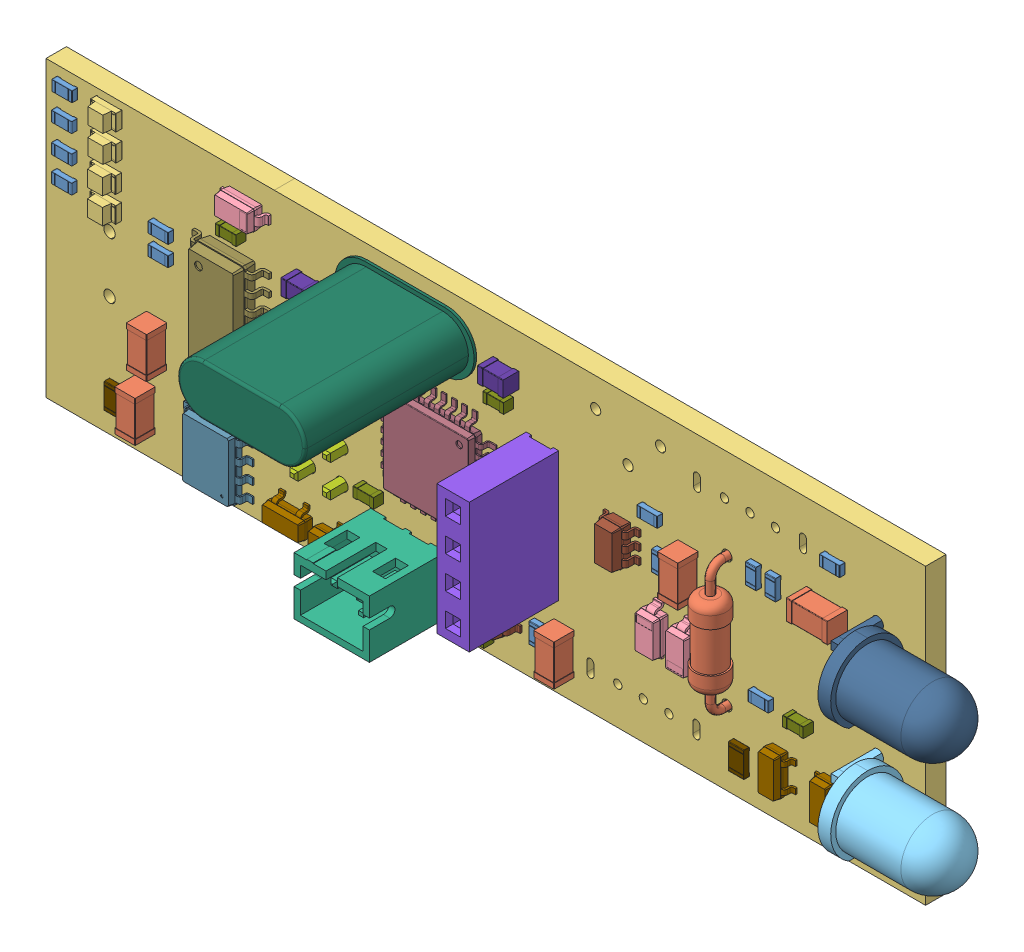
SolidWorks assembly RPM, configuration Default. Lengths in mm.
Overall size (76.12 23 23.34).
114 component instances, 21 part files, 0 mates.
Components (placement in the parent):
- RPM.step-1: RPM.step [Default] at origin size (76.12 23 23.34)
  - Mini_USB.step-1: Mini_USB.step [Default] at (183.35 -104.2 -0.05) x (1 0 0) z (0 0 -1) size (10.5 10.7 3.9)
    - SOLID.step-1: SOLID.step [Default] at origin size (10.5 10.7 3.9)
  - C_1206_3216Metric.step-1: C_1206_3216Metric.step [Default] at (220.5 -112.4 1.65) x (0 -1 0) z (0 0 1) size (3.2 1.6 1.6)
    - SOLID-0.step-1: SOLID-0.step [Default] at origin size (3.2 1.6 1.6)
  - C_1206_3216Metric.step-2: C_1206_3216Metric.step [Default] at (230.2 -102.2 1.65) x (0 1 0) z (0 0 1) size (3.2 1.6 1.6)
    - SOLID-0.step-1: SOLID-0.step [Default] at origin size (3.2 1.6 1.6)
  - C_1206_3216Metric.step-3: C_1206_3216Metric.step [Default] at (187.7 -112.275 1.65) x (0 1 0) z (0 0 1) size (3.2 1.6 1.6)
    - SOLID-0.step-1: SOLID-0.step [Default] at origin size (3.2 1.6 1.6)
  - C_1206_3216Metric.step-4: C_1206_3216Metric.step [Default] at (188.6 -107.5 1.65) x (0 1 0) z (0 0 1) size (3.2 1.6 1.6)
    - SOLID-0.step-1: SOLID-0.step [Default] at origin size (3.2 1.6 1.6)
  - LED_0805_2012Metric.step-1: LED_0805_2012Metric.step [Default] at (184.8625 -98.1 1.65) x (-1 0 0) z (0 0 1) size (2 1.25 1.1)
    - SOLID-1.step-1: SOLID-1.step [Default] at origin size (2 1.25 1.1)
  - LED_0805_2012Metric.step-2: LED_0805_2012Metric.step [Default] at (184.8625 -100.125 1.65) x (-1 0 0) z (0 0 1) size (2 1.25 1.1)
    - SOLID-1.step-1: SOLID-1.step [Default] at origin size (2 1.25 1.1)
  - D_SOD-123.step-1: D_SOD-123.step [Default] at (195.65 -94.8 1.65) x (-1 0 0) z (0 0 1) size (3.8 1.6 1.25)
    - SOLID-2.step-1: SOLID-2.step [Default] at origin size (3.8 1.6 1.25)
  - D_SOD-123.step-2: D_SOD-123.step [Default] at (228 -107.25 1.65) x (0 -1 0) z (0 0 1) size (3.8 1.6 1.25)
    - SOLID-2.step-1: SOLID-2.step [Default] at origin size (3.8 1.6 1.25)
  - D_SOD-123.step-3: D_SOD-123.step [Default] at (230.4 -107.25 1.65) x (0 1 0) z (0 0 1) size (3.8 1.6 1.25)
    - SOLID-2.step-1: SOLID-2.step [Default] at origin size (3.8 1.6 1.25)
  - LED_0805_2012Metric.step-3: LED_0805_2012Metric.step [Default] at (184.8875 -95.95 1.65) size (2 1.25 1.1)
    - SOLID-1.step-1: SOLID-1.step [Default] at origin size (2 1.25 1.1)
  - LED_D5.0mm_Horizontal_O1.27mm_Z3.0mm_IRGrey.step-1: LED_D5.0mm_Horizontal_O1.27mm_Z3.0mm_IRGrey.step [Default] at (245 -110 1.65) x (0 1 0) z (0 0 1) size (5.4 10.17 7.9)
    - SOLID-3.step-1: SOLID-3.step [Default] at origin size (5.4 10.17 7.9)
  - LED_0805_2012Metric.step-4: LED_0805_2012Metric.step [Default] at (184.8875 -93.85 1.65) size (2 1.25 1.1)
    - SOLID-1.step-1: SOLID-1.step [Default] at origin size (2 1.25 1.1)
  - JST_PH_B2B-PH-K_1x02_P2.00mm_Vertical.step-1: JST_PH_B2B-PH-K_1x02_P2.00mm_Vertical.step [Default] at (207.3 -112.2 1.65) size (5.9 4.55 9.4)
    - SOLID-4.step-1: SOLID-4.step [Default] at origin size (5.9 4.55 9.4)
  - PinHeader_2x03_P2.54mm_Vertical.step-1: PinHeader_2x03_P2.54mm_Vertical.step [Default] at (203.025 -104.975 -0.05) x (-1 0 0) z (0 0 -1) size (5.08 7.62 11.54)
    - SOLID-5.step-1: SOLID-5.step [Default] at origin size (5.08 7.62 11.54)
  - PinSocket_1x04_P2.54mm_Vertical.step-1: PinSocket_1x04_P2.54mm_Vertical.step [Default] at (218.8 -100.5 1.65) size (2.54 10.16 10.1)
    - SOLID-6.step-1: SOLID-6.step [Default] at origin size (2.54 10.16 10.1)
  - SOT-23.step-1: SOT-23.step [Default] at (203.05 -113.9 1.65) x (0 1 0) z (0 0 1) size (2.5 3 1.2)
    - SOLID-7.step-1: SOLID-7.step [Default] at origin size (2.5 3 1.2)
  - SOT-23.step-2: SOT-23.step [Default] at (199.45 -113.9 1.65) x (0 -1 0) z (0 0 1) size (2.5 3 1.2)
    - SOLID-7.step-1: SOLID-7.step [Default] at origin size (2.5 3 1.2)
  - SOT-23.step-3: SOT-23.step [Default] at (241.5 -112 1.65) size (2.5 3 1.2)
    - SOLID-7.step-1: SOLID-7.step [Default] at origin size (2.5 3 1.2)
  - SOT-23.step-4: SOT-23.step [Default] at (237.5 -112 1.65) x (-1 0 0) z (0 0 1) size (2.5 3 1.2)
    - SOLID-7.step-1: SOLID-7.step [Default] at origin size (2.5 3 1.2)
  - LED_D5.0mm_Horizontal_O1.27mm_Z3.0mm_Clear.step-1: LED_D5.0mm_Horizontal_O1.27mm_Z3.0mm_Clear.step [Default] at (245 -101 1.65) x (0 1 0) z (0 0 1) size (5.4 10.17 7.9)
    - SOLID-8.step-1: SOLID-8.step [Default] at origin size (5.4 10.17 7.9)
  - SOT-23-6.step-1: SOT-23-6.step [Default] at (215.8 -111.8 1.65) x (-1 0 0) z (0 0 1) size (2.8 2.9 1.55)
    - SOLID-9.step-1: SOLID-9.step [Default] at origin size (2.8 2.9 1.55)
  - SOIC-16_3.9x9.9mm_P1.27mm.step-1: SOIC-16_3.9x9.9mm_P1.27mm.step [Default] at (194.575 -103.025 1.65) size (6 9.9 1.75)
    - SOLID-10.step-1: SOLID-10.step [Default] at origin size (6 9.9 1.75)
  - SOT-23-6.step-2: SOT-23-6.step [Default] at (225.1 -102.55 1.65) x (-1 0 0) z (0 0 1) size (2.8 2.9 1.55)
    - SOLID-9.step-1: SOLID-9.step [Default] at origin size (2.8 2.9 1.55)
  - TQFP-32_7x7mm_P0.8mm.step-1: TQFP-32_7x7mm_P0.8mm.step [Default] at (210.75 -104.25 1.65) x (0 -1 0) z (0 0 1) size (9 9 1.1)
    - SOLID-11.step-1: SOLID-11.step [Default] at origin size (9 9 1.1)
  - HTSOP-8-1EP_3.9x4.9mm_Pitch1.27mm.step-1: HTSOP-8-1EP_3.9x4.9mm_Pitch1.27mm.step [Default] at (193.5 -112.605 1.65) x (-1 0 0) z (0 0 1) size (5.4 4.9 1.1)
    - SOLID-12.step-1: SOLID-12.step [Default] at origin size (5.4 4.9 1.1)
  - Crystal_HC18-U_Vertical.step-1: Crystal_HC18-U_Vertical.step [Default] at (210.75 -96 1.65) x (-1 0 0) z (0 0 1) size (10.9 4.65 16)
    - SOLID-13.step-1: SOLID-13.step [Default] at origin size (10.9 4.65 16)
  - C_0603_1608Metric.step-1: C_0603_1608Metric.step [Default] at (214.1875 -114.4 1.65) size (1.6 0.8 0.8)
    - SOLID-14.step-1: SOLID-14.step [Default] at origin size (1.6 0.8 0.8)
  - C_0603_1608Metric.step-2: C_0603_1608Metric.step [Default] at (194.4125 -109.1 1.65) size (1.6 0.8 0.8)
    - SOLID-14.step-1: SOLID-14.step [Default] at origin size (1.6 0.8 0.8)
  - C_0603_1608Metric.step-3: C_0603_1608Metric.step [Default] at (194.7875 -96.85 1.65) x (-1 0 0) z (0 0 1) size (1.6 0.8 0.8)
    - SOLID-14.step-1: SOLID-14.step [Default] at origin size (1.6 0.8 0.8)
  - C_0603_1608Metric.step-4: C_0603_1608Metric.step [Default] at (200.1625 -102.4 1.65) x (-1 0 0) z (0 0 1) size (1.6 0.8 0.8)
    - SOLID-14.step-1: SOLID-14.step [Default] at origin size (1.6 0.8 0.8)
  - C_0603_1608Metric.step-5: C_0603_1608Metric.step [Default] at (205.5625 -109.275 1.65) x (-1 0 0) z (0 0 1) size (1.6 0.8 0.8)
    - SOLID-14.step-1: SOLID-14.step [Default] at origin size (1.6 0.8 0.8)
  - C_0603_1608Metric.step-6: C_0603_1608Metric.step [Default] at (215.7375 -97.75 1.65) size (1.6 0.8 0.8)
    - SOLID-14.step-1: SOLID-14.step [Default] at origin size (1.6 0.8 0.8)
  - C_0805_2012Metric.step-1: C_0805_2012Metric.step [Default] at (215.9625 -96 1.65) x (-1 0 0) z (0 0 1) size (2 1.25 1.25)
    - SOLID-15.step-1: SOLID-15.step [Default] at origin size (2 1.25 1.25)
  - C_0805_2012Metric.step-2: C_0805_2012Metric.step [Default] at (200.5625 -97.75 1.65) size (2 1.25 1.25)
    - SOLID-15.step-1: SOLID-15.step [Default] at origin size (2 1.25 1.25)
  - C_1206_3216Metric.step-5: C_1206_3216Metric.step [Default] at (241.1 -99.5 1.65) size (3.2 1.6 1.6)
    - SOLID-0.step-1: SOLID-0.step [Default] at origin size (3.2 1.6 1.6)
  - C_0603_1608Metric.step-7: C_0603_1608Metric.step [Default] at (239.2125 -108 1.65) size (1.6 0.8 0.8)
    - SOLID-14.step-1: SOLID-14.step [Default] at origin size (1.6 0.8 0.8)
  - R_0805_2012Metric.step-1: R_0805_2012Metric.step [Default] at (212.8 -111.6375 1.65) x (0 -1 0) z (0 0 1) size (2 1.2 0.45)
    - SOLID-16.step-1: SOLID-16.step [Default] at origin size (2 1.2 0.45)
  - R_0603_1608Metric.step-1: R_0603_1608Metric.step [Default] at (218.6 -112.2875 1.65) x (0 -1 0) z (0 0 1) size (1.6 0.8 0.45)
    - SOLID-17.step-1: SOLID-17.step [Default] at origin size (1.6 0.8 0.45)
  - R_0603_1608Metric.step-2: R_0603_1608Metric.step [Default] at (189.1375 -99.7 1.65) size (1.6 0.8 0.45)
    - SOLID-17.step-1: SOLID-17.step [Default] at origin size (1.6 0.8 0.45)
  - R_0603_1608Metric.step-3: R_0603_1608Metric.step [Default] at (189.1375 -101.275 1.65) size (1.6 0.8 0.45)
    - SOLID-17.step-1: SOLID-17.step [Default] at origin size (1.6 0.8 0.45)
  - R_0603_1608Metric.step-4: R_0603_1608Metric.step [Default] at (237.075 -99.7875 1.65) x (0 1 0) z (0 0 1) size (1.6 0.8 0.45)
    - SOLID-17.step-1: SOLID-17.step [Default] at origin size (1.6 0.8 0.45)
  - R_0603_1608Metric.step-5: R_0603_1608Metric.step [Default] at (181.5875 -98.15 1.65) size (1.6 0.8 0.45)
    - SOLID-17.step-1: SOLID-17.step [Default] at origin size (1.6 0.8 0.45)
  - R_0603_1608Metric.step-6: R_0603_1608Metric.step [Default] at (236.1375 -107.975 1.65) x (-1 0 0) z (0 0 1) size (1.6 0.8 0.45)
    - SOLID-17.step-1: SOLID-17.step [Default] at origin size (1.6 0.8 0.45)
  - R_0603_1608Metric.step-7: R_0603_1608Metric.step [Default] at (235.55 -99.7875 1.65) x (0 1 0) z (0 0 1) size (1.6 0.8 0.45)
    - SOLID-17.step-1: SOLID-17.step [Default] at origin size (1.6 0.8 0.45)
  - R_0603_1608Metric.step-8: R_0603_1608Metric.step [Default] at (181.5875 -100.125 1.65) size (1.6 0.8 0.45)
    - SOLID-17.step-1: SOLID-17.step [Default] at origin size (1.6 0.8 0.45)
  - R_0603_1608Metric.step-9: R_0603_1608Metric.step [Default] at (200.1625 -100.85 1.65) size (1.6 0.8 0.45)
    - SOLID-17.step-1: SOLID-17.step [Default] at origin size (1.6 0.8 0.45)
  - R_0603_1608Metric.step-10: R_0603_1608Metric.step [Default] at (228.2 -102.5875 1.65) x (0 1 0) z (0 0 1) size (1.6 0.8 0.45)
    - SOLID-17.step-1: SOLID-17.step [Default] at origin size (1.6 0.8 0.45)
  - R_0603_1608Metric.step-11: R_0603_1608Metric.step [Default] at (227.43 -99.8 1.65) x (-1 0 0) z (0 0 1) size (1.6 0.8 0.45)
    - SOLID-17.step-1: SOLID-17.step [Default] at origin size (1.6 0.8 0.45)
  - R_0805_2012Metric.step-2: R_0805_2012Metric.step [Default] at (234.4 -112.8625 1.65) x (0 -1 0) z (0 0 1) size (2 1.2 0.45)
    - SOLID-16.step-1: SOLID-16.step [Default] at origin size (2 1.2 0.45)
  - R_Axial_DIN0207_L6.3mm_D2.5mm_P10.16mm_Horizontal.step-1: R_Axial_DIN0207_L6.3mm_D2.5mm_P10.16mm_Horizontal.step [Default] at (233.2 -109.96 1.65) x (0 1 0) z (0 0 1) size (10.76 2.5 5.5)
    - SOLID-18.step-1: SOLID-18.step [Default] at origin size (10.76 2.5 5.5)
  - R_0603_1608Metric.step-12: R_0603_1608Metric.step [Default] at (241.7125 -96 1.65) size (1.6 0.8 0.45)
    - SOLID-17.step-1: SOLID-17.step [Default] at origin size (1.6 0.8 0.45)
  - R_0603_1608Metric.step-13: R_0603_1608Metric.step [Default] at (181.6125 -93.85 1.65) size (1.6 0.8 0.45)
    - SOLID-17.step-1: SOLID-17.step [Default] at origin size (1.6 0.8 0.45)
  - R_0603_1608Metric.step-14: R_0603_1608Metric.step [Default] at (181.5875 -95.95 1.65) size (1.6 0.8 0.45)
    - SOLID-17.step-1: SOLID-17.step [Default] at origin size (1.6 0.8 0.45)
  - R_0805_2012Metric.step-3: R_0805_2012Metric.step [Default] at (245.5625 -104 1.65) size (2 1.2 0.45)
    - SOLID-16.step-1: SOLID-16.step [Default] at origin size (2 1.2 0.45)
  - R_0805_2012Metric.step-4: R_0805_2012Metric.step [Default] at (185.525 -112.8625 1.65) x (0 1 0) z (0 0 1) size (2 1.2 0.45)
    - SOLID-16.step-1: SOLID-16.step [Default] at origin size (2 1.2 0.45)
  - COMPOUND.step-1: COMPOUND.step [Default] at origin size (68.87 23 1.6)
